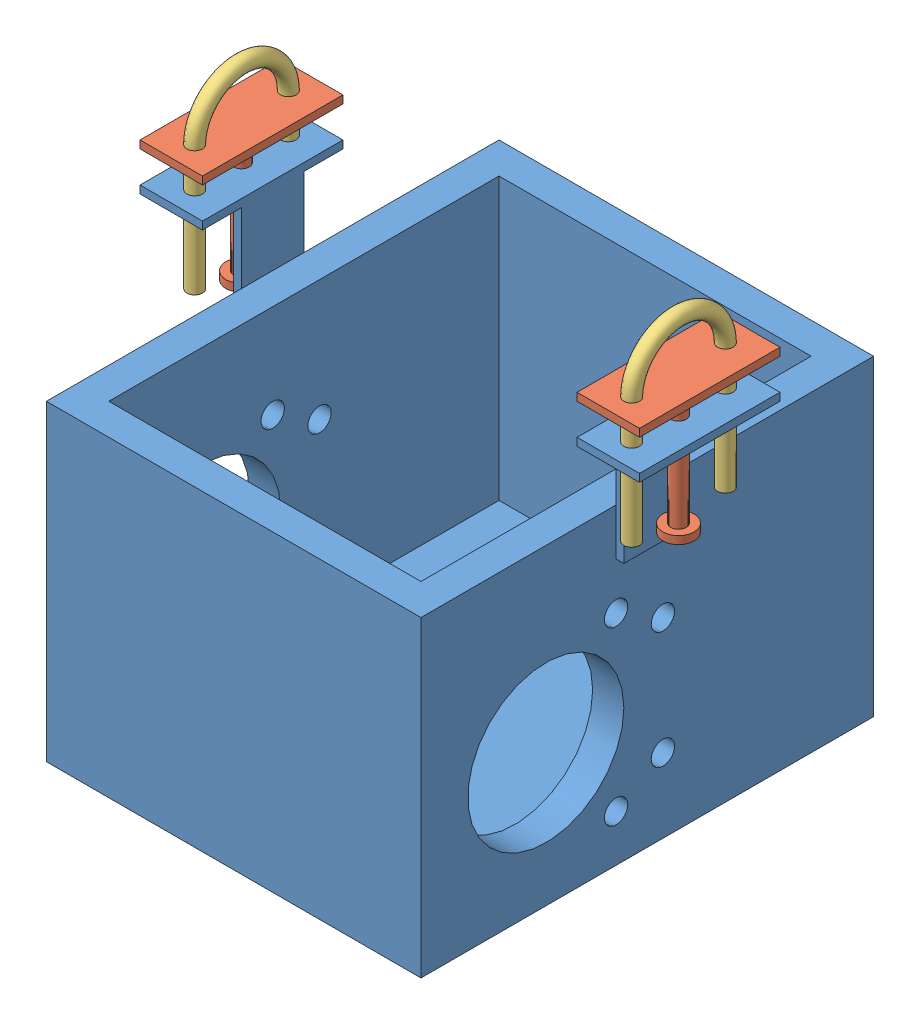
SolidWorks assembly CompleteCase, configuration Predeterminado. Lengths in mm.
Overall size (32 31 29).
5 component instances, 3 part files, 12 mates.
Components (placement in the parent):
- Case-1: Case [Predeterminado] at (-1.4144 -13.5431 32) size (32 25 29)
- Lock-1: Lock [Predeterminado] at (12.5856 13.4569 32) x (0 0 -1) z (1 0 0) size (9 9 4)
- Lock-2: Lock [Predeterminado] at (-15.4144 13.4569 32) x (0 0 -1) z (1 0 0) size (9 9 4)
- U-1: U [Predeterminado] at (-15.4144 5.9569 32) x (0 0 -1) z (1 0 0) size (7 11.5 1)
- U-2: U [Predeterminado] at (12.5856 5.9569 32) x (0 0 -1) z (1 0 0) size (7 11.5 1)
Mates (geometry in assembly coordinates):
- Concentric2: concentric anti-aligned: cylinder of Case-1 through (-15.4144 9.5427 29) axis (0 1 0) radius 0.5; cylinder of U-1 through (-15.4144 13.9569 29) axis (0 -1 0) radius 0.5
- Concentric3: concentric aligned: cylinder of Case-1 through (-15.4144 9.5427 35) axis (0 1 0) radius 0.5; cylinder of U-1 through (-15.4144 5.9569 35) axis (0 1 0) radius 0.5
- Concentric4: concentric aligned: cylinder of Lock-2 through (-15.4144 13.9569 29) axis (0 -1 0) radius 0.5; cylinder of U-1 through (-15.4144 13.9569 29) axis (0 -1 0) radius 0.5
- Concentric5: concentric anti-aligned: cylinder of Lock-2 through (-15.4144 13.9569 35) axis (0 -1 0) radius 0.5; cylinder of U-1 through (-15.4144 5.9569 35) axis (0 1 0) radius 0.5
- Coincident2: coincident anti-aligned: plane of Lock-2 through (-15.4144 13.9569 32) normal (0 1 0); circle of U-1
- Distance1: distance = 2 mm anti-aligned: plane of Lock-2 through (-15.4144 13.4569 32) normal (0 -1 0); plane of Case-1 through (-17.4144 11.4569 36.5) normal (0 1 0)
- Concentric7: concentric anti-aligned: cylinder of Lock-1 through (12.5856 13.9569 35) axis (0 -1 0) radius 0.5; cylinder of U-2 through (12.5856 5.9569 35) axis (0 1 0) radius 0.5
- Concentric8: concentric aligned: cylinder of Case-1 through (12.5856 9.5427 35) axis (0 1 0) radius 0.5; cylinder of U-2 through (12.5856 5.9569 35) axis (0 1 0) radius 0.5
- Concentric9: concentric anti-aligned: cylinder of Case-1 through (12.5856 9.5427 29) axis (0 1 0) radius 0.5; cylinder of Lock-1 through (12.5856 13.9569 29) axis (0 -1 0) radius 0.5
- Concentric10: concentric anti-aligned: cylinder of Case-1 through (12.5856 9.5427 29) axis (0 1 0) radius 0.5; cylinder of U-2 through (12.5856 13.9569 29) axis (0 -1 0) radius 0.5
- Coincident4: coincident aligned: plane of Lock-1 through (12.5856 13.9569 32) normal (0 1 0); circle of U-2
- Distance2: distance = 2 mm: plane of Case-1 through (14.5856 11.4569 36.5) normal (0 1 0); line of Lock-1 through (14.5856 13.4569 36.5) axis (0 0 -1)
